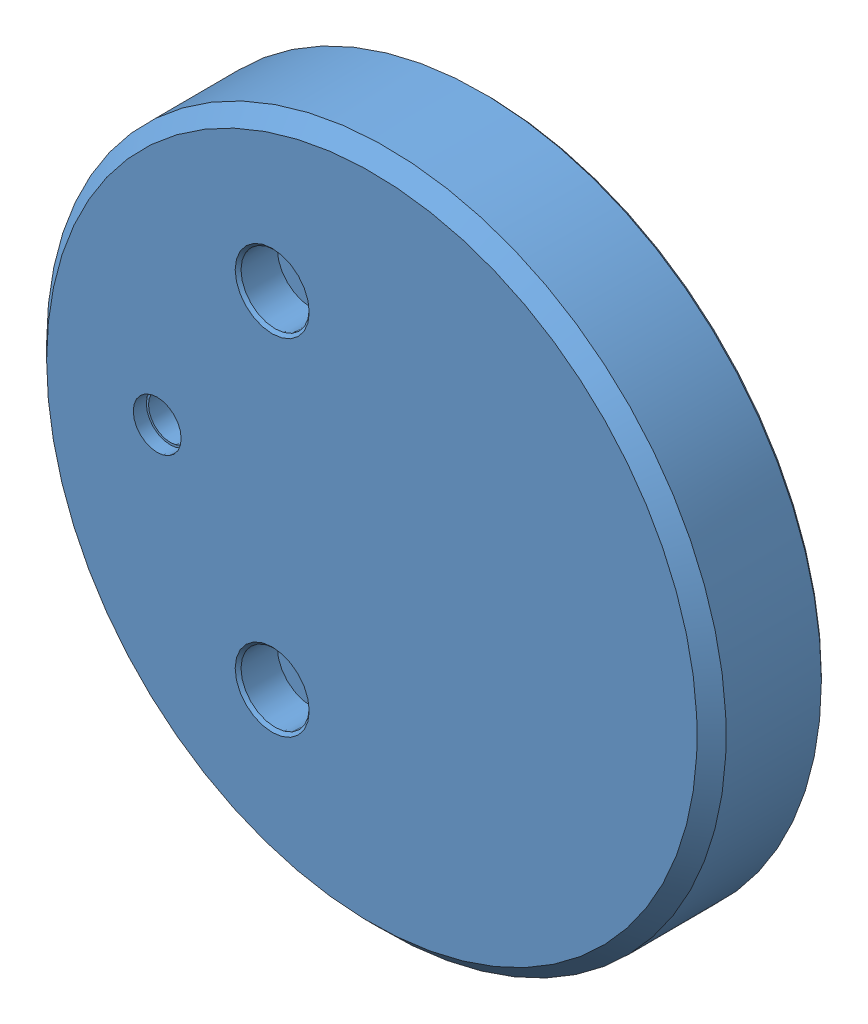
SolidWorks assembly 装配效果, configuration 默认. Lengths in mm.
Overall size (46.8 46.8 7.81).
93 component instances, 18 part files, 0 mates.
Components (placement in the parent):
- 6锂电尾部电池架-1: 6锂电尾部电池架 [默认] at origin size (46.8 46.8 7.81)
- PCB1.step-1: PCB1.step [默认] at (78.0946 78.0068 2.1578) size (42.87 42.87 4.92)
  - D5.step-1: D5.step [默认] at origin size (3.7 1.6 1.43)
    - SOD123.step-1: SOD123.step [默认] at (20.5742 30.9882 0) x (1 0 0) z (0 0 1) size (3.7 1.6 1.43)
  - D4.step-1: D4.step [默认] at origin size (3.7 1.6 1.43)
    - SOD123.step-1: SOD123.step [默认] at (20.5738 29.0828 0) x (-1 0 0) z (0 0 1) size (3.7 1.6 1.43)
  - D3.step-1: D3.step [默认] at origin size (1.6 3.7 1.43)
    - SOD123.step-1: SOD123.step [默认] at (26.4158 28.5752 0) x (0 1 0) z (0 0 1) size (3.7 1.6 1.43)
  - Q1.step-1: Q1.step [默认] at origin size (2.03 2.03 0.5)
    - 539740560.step-1: 539740560.step [默认] at (35.052 26.543 0.05) size (2.03 2.03 0.5)
      - Extruded.step-1: Extruded.step [默认] at origin size (2.03 2.03 0.5)
  - Q2.step-1: Q2.step [默认] at origin size (2.03 2.03 0.5)
    - 539740560.step-1: 539740560.step [默认] at (35.052 30.226 0.05) size (2.03 2.03 0.5)
      - Extruded.step-1: Extruded.step [默认] at origin size (2.03 2.03 0.5)
  - Q3.step-1: Q3.step [默认] at origin size (2.2 1.35 1)
    - 539740304.step-1: 539740304.step [默认] at (30.607 28.575 0.1) size (2.2 1.35 1)
      - Extruded-0.step-1: Extruded-0.step [默认] at origin size (2.2 1.35 1)
  - R1.step-1: R1.step [默认] at origin size (0.55 1.15 0.41)
    - User_Library-RES_1005-0402.step-1: User_Library-RES_1005-0402.step [默认] at (37.592 26.543 0) x (0 1 0) z (1 0 0) size (1.15 0.41 0.55)
  - R2.step-1: R2.step [默认] at origin size (0.55 1.15 0.41)
    - User_Library-RES_1005-0402.step-1: User_Library-RES_1005-0402.step [默认] at (37.592 30.226 0) x (0 1 0) z (1 0 0) size (1.15 0.41 0.55)
  - R3.step-1: R3.step [默认] at origin size (1.15 0.55 0.41)
    - User_Library-RES_1005-0402.step-1: User_Library-RES_1005-0402.step [默认] at (31.115 26.162 0) x (-1 0 0) z (0 1 0) size (1.15 0.41 0.55)
  - R4.step-1: R4.step [默认] at origin size (1.15 0.55 0.41)
    - User_Library-RES_1005-0402.step-1: User_Library-RES_1005-0402.step [默认] at (30.607 30.988 0) x (1 0 0) z (0 -1 0) size (1.15 0.41 0.55)
  - C1.step-1: C1.step [默认] at origin size (0.8 1.6 0.3)
    - User_Library-0603_SMD_Capacitor.step-1: User_Library-0603_SMD_Capacitor.step [默认] at (31.496 33.401 0) x (0 -1 0) z (-1 0 0) size (1.6 0.3 0.8)
  - C2.step-1: C2.step [默认] at origin size (0.6 1 0.2)
    - 0402_SMD_Capacitor.step-1: 0402_SMD_Capacitor.step [默认] at (25.527 34.9424 0) x (0 1 0) z (1 0 0) size (1 0.2 0.6)
  - C3.step-1: C3.step [默认] at origin size (2 1.25 0.78)
    - User_Library-0805_SMD_Capacitor.step-1: User_Library-0805_SMD_Capacitor.step [默认] at (22.9875 36.576 -0.01) x (1 0 0) z (0 -1 0) size (2 0.78 1.25)
  - C4.step-1: C4.step [默认] at origin size (0.6 1 0.2)
    - 0402_SMD_Capacitor.step-1: 0402_SMD_Capacitor.step [默认] at (20.701 33.0374 0) x (0 1 0) z (1 0 0) size (1 0.2 0.6)
  - C5.step-1: C5.step [默认] at origin size (1.6 0.8 0.3)
    - User_Library-0603_SMD_Capacitor.step-1: User_Library-0603_SMD_Capacitor.step [默认] at (24.511 31.623 0) x (1 0 0) z (0 -1 0) size (1.6 0.3 0.8)
  - L1.step-1: L1.step [默认] at origin size (4.06 4.06 1.95)
    - 539740944.step-1: 539740944.step [默认] at (28.448 33.909 0.05) size (4.06 4.06 1.95)
      - Extruded-1.step-1: Extruded-1.step [默认] at origin size (4.06 4.06 1.95)
  - R5.step-1: R5.step [默认] at origin size (0.55 1.15 0.41)
    - User_Library-RES_1005-0402.step-1: User_Library-RES_1005-0402.step [默认] at (19.177 33.02 0) x (0 1 0) z (1 0 0) size (1.15 0.41 0.55)
  - U1.step-1: U1.step [默认] at origin size (2.08 2.08 0.75)
    - 539740432.step-1: 539740432.step [默认] at (23.114 33.909 0.05) size (2.08 2.08 0.75)
      - Extruded-2.step-1: Extruded-2.step [默认] at origin size (2.08 2.08 0.75)
  - D1.step-1: D1.step [默认] at origin size (1.6 0.8 0.6)
    - User_Library-LED_0603_R.step-1: User_Library-LED_0603_R.step [默认] at (7.1121 22.8601 0) x (1 0 0) z (0 0 1) size (1.6 0.8 0.6)
      - User_Library-LED_0603_R_Pocket002.step-1: User_Library-LED_0603_R_Pocket002.step [默认] at origin size (0.4 0.8 0.2)
      - User_Library-LED_0603_R_Pad004.step-1: User_Library-LED_0603_R_Pad004.step [默认] x (1 0 0) z (0 0 -1) size (0.4 0.8 0)
      - User_Library-LED_0603_R_Fillet.step-1: User_Library-LED_0603_R_Fillet.step [默认] at origin size (1 0.7 0.4)
      - User_Library-LED_0603_R_Pocket001.step-1: User_Library-LED_0603_R_Pocket001.step [默认] at origin size (0.4 0.8 0.2)
      - User_Library-LED_0603_R_Pad.step-1: User_Library-LED_0603_R_Pad.step [默认] at origin size (0.8 0.8 0.2)
  - R6.step-1: R6.step [默认] at origin size (1.15 0.55 0.41)
    - User_Library-RES_1005-0402.step-1: User_Library-RES_1005-0402.step [默认] at (19.558 34.925 0) x (1 0 0) z (0 -1 0) size (1.15 0.41 0.55)
  - Q4.step-1: Q4.step [默认] at origin size (2.03 2.03 0.5)
    - 539740560.step-1: 539740560.step [默认] at (34.29 15.24 0.05) size (2.03 2.03 0.5)
      - Extruded.step-1: Extruded.step [默认] at origin size (2.03 2.03 0.5)
  - Q5.step-1: Q5.step [默认] at origin size (1.35 2.2 1)
    - 539740688.step-1: 539740688.step [默认] at (30.48 15.24 0.1) size (1.35 2.2 1)
      - Extruded-3.step-1: Extruded-3.step [默认] at origin size (1.35 2.2 1)
  - R7.step-1: R7.step [默认] at origin size (0.55 1.15 0.41)
    - User_Library-RES_1005-0402.step-1: User_Library-RES_1005-0402.step [默认] at (36.83 15.24 0) x (0 -1 0) z (-1 0 0) size (1.15 0.41 0.55)
  - R8.step-1: R8.step [默认] at origin size (0.55 1.15 0.41)
    - User_Library-RES_1005-0402.step-1: User_Library-RES_1005-0402.step [默认] at (28.067 15.24 0) x (0 1 0) z (1 0 0) size (1.15 0.41 0.55)
  - C6.step-1: C6.step [默认] at origin size (0.8 1.6 0.3)
    - User_Library-0603_SMD_Capacitor.step-1: User_Library-0603_SMD_Capacitor.step [默认] at (29.972 8.509 0) x (0 -1 0) z (-1 0 0) size (1.6 0.3 0.8)
  - C7.step-1: C7.step [默认] at origin size (0.6 1 0.2)
    - 0402_SMD_Capacitor.step-1: 0402_SMD_Capacitor.step [默认] at (23.876 9.7616 0) x (0 -1 0) z (-1 0 0) size (1 0.2 0.6)
  - C8.step-1: C8.step [默认] at origin size (0.6 1 0.2)
    - 0402_SMD_Capacitor.step-1: 0402_SMD_Capacitor.step [默认] at (20.574 6.2404 0) x (0 1 0) z (1 0 0) size (1 0.2 0.6)
  - C9.step-1: C9.step [默认] at origin size (1.6 0.8 0.3)
    - User_Library-0603_SMD_Capacitor.step-1: User_Library-0603_SMD_Capacitor.step [默认] at (22.987 6.35 0) x (1 0 0) z (0 -1 0) size (1.6 0.3 0.8)
  - L2.step-1: L2.step [默认] at origin size (4.06 4.06 1.95)
    - 539740944.step-1: 539740944.step [默认] at (26.797 8.763 0.05) size (4.06 4.06 1.95)
      - Extruded-1.step-1: Extruded-1.step [默认] at origin size (4.06 4.06 1.95)
  - R9.step-1: R9.step [默认] at origin size (0.55 1.15 0.41)
    - User_Library-RES_1005-0402.step-1: User_Library-RES_1005-0402.step [默认] at (19.177 6.223 0) x (0 1 0) z (1 0 0) size (1.15 0.41 0.55)
  - U2.step-1: U2.step [默认] at origin size (2.08 2.08 0.75)
    - 539740432.step-1: 539740432.step [默认] at (21.717 8.89 0.05) size (2.08 2.08 0.75)
      - Extruded-2.step-1: Extruded-2.step [默认] at origin size (2.08 2.08 0.75)
  - C10.step-1: C10.step [默认] at origin size (2 1.25 0.78)
    - User_Library-0805_SMD_Capacitor.step-1: User_Library-0805_SMD_Capacitor.step [默认] at (34.2895 12.446 -0.01) x (-1 0 0) z (0 1 0) size (2 0.78 1.25)
  - D2.step-1: D2.step [默认] at origin size (1.6 0.8 0.6)
    - User_Library-LED_0603_R.step-1: User_Library-LED_0603_R.step [默认] at (7.1121 20.9551 0) x (1 0 0) z (0 0 1) size (1.6 0.8 0.6)
      - User_Library-LED_0603_R_Pocket002.step-1: User_Library-LED_0603_R_Pocket002.step [默认] at origin size (0.4 0.8 0.2)
      - User_Library-LED_0603_R_Pad004.step-1: User_Library-LED_0603_R_Pad004.step [默认] x (1 0 0) z (0 0 -1) size (0.4 0.8 0)
      - User_Library-LED_0603_R_Fillet.step-1: User_Library-LED_0603_R_Fillet.step [默认] at origin size (1 0.7 0.4)
      - User_Library-LED_0603_R_Pocket001.step-1: User_Library-LED_0603_R_Pocket001.step [默认] at origin size (0.4 0.8 0.2)
      - User_Library-LED_0603_R_Pad.step-1: User_Library-LED_0603_R_Pad.step [默认] at origin size (0.8 0.8 0.2)
  - R10.step-1: R10.step [默认] at origin size (0.55 1.15 0.41)
    - User_Library-RES_1005-0402.step-1: User_Library-RES_1005-0402.step [默认] at (19.177 9.779 0) x (0 -1 0) z (-1 0 0) size (1.15 0.41 0.55)
  - Free-Models.step-1: Free-Models.step [默认] at origin size (10.8 10.8 4.06)
    - 539740176.step-1: 539740176.step [默认] at (21.895 21.895 0) size (10.8 10.8 4.06)
      - Cylinder.step-1: Cylinder.step [默认] at origin size (10.8 10.8 4.06)
  - Board.step-1: Board.step [默认] at (0 0 -0.8645) size (42.87 42.87 0.86)
